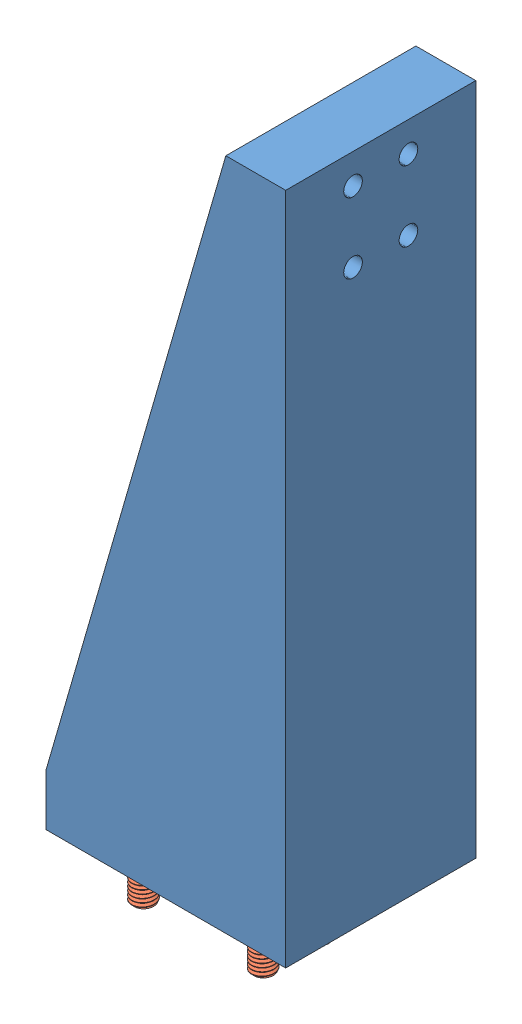
SolidWorks assembly Assem1, configuration Default. Lengths in mm.
Overall size (32 101.12 25.4).
5 component instances, 2 part files, 12 mates.
Components (placement in the parent):
- M40_Calibration Stand-1: M40_Calibration Stand [Default] at origin size (32 90 25.4)
- M43_91292A029_18-8 Stainless Steel Socket Head Screw-1: M43_91292A029_18-8 Stainless Steel Socket Head Screw [91292A029] at (20 -11 9) x (1 0 0) z (0 -1 0) size (5.5 5.5 21.26)
- M43_91292A029_18-8 Stainless Steel Socket Head Screw-2: M43_91292A029_18-8 Stainless Steel Socket Head Screw [91292A029] at (4 -11 9) x (1 0 0) z (0 -1 0) size (5.5 5.5 21.26)
- M43_91292A029_18-8 Stainless Steel Socket Head Screw-3: M43_91292A029_18-8 Stainless Steel Socket Head Screw [91292A029] at (4 -11 16.4) x (1 0 0) z (0 -1 0) size (5.5 5.5 21.26)
- M43_91292A029_18-8 Stainless Steel Socket Head Screw-4: M43_91292A029_18-8 Stainless Steel Socket Head Screw [91292A029] at (20 -11 16.4) x (1 0 0) z (0 -1 0) size (5.5 5.5 21.26)
Mates (geometry in assembly coordinates):
- Concentric1: concentric anti-aligned: cylinder of M40_Calibration Stand-1 through (20 -0.001 9) axis (0 1 0) radius 1.55; cylinder of M43_91292A029_18-8 Stainless Steel Socket Head Screw-1 through (20 10 9) axis (0 -1 0) radius 2.75
- Coincident1: coincident anti-aligned: plane of M40_Calibration Stand-1 through (0 7 25.4) normal (0 1 0); plane of M43_91292A029_18-8 Stainless Steel Socket Head Screw-1 through (20 7 9) normal (0 -1 0)
- Parallel1: parallel aligned: plane of M40_Calibration Stand-1 through (0 0 25.4) normal (-1 0 0); plane of M43_91292A029_18-8 Stainless Steel Socket Head Screw-1 through (21.25 8.125 9.7217) normal (-1 0 0)
- Concentric2: concentric anti-aligned: cylinder of M40_Calibration Stand-1 through (20 -0.001 16.4) axis (0 1 0) radius 1.55; cylinder of M43_91292A029_18-8 Stainless Steel Socket Head Screw-4 through (20 10 16.4) axis (0 -1 0) radius 2.75
- Coincident3: coincident anti-aligned: plane of M40_Calibration Stand-1 through (0 7 25.4) normal (0 1 0); plane of M43_91292A029_18-8 Stainless Steel Socket Head Screw-4 through (20 7 16.4) normal (0 -1 0)
- Parallel2: parallel aligned: plane of M40_Calibration Stand-1 through (0 0 25.4) normal (-1 0 0); plane of M43_91292A029_18-8 Stainless Steel Socket Head Screw-4 through (21.25 8.125 17.1217) normal (-1 0 0)
- Concentric3: concentric anti-aligned: cylinder of M40_Calibration Stand-1 through (4 -0.001 16.4) axis (0 1 0) radius 1.55; cylinder of M43_91292A029_18-8 Stainless Steel Socket Head Screw-3 through (4 10 16.4) axis (0 -1 0) radius 2.75
- Coincident6: coincident anti-aligned: plane of M40_Calibration Stand-1 through (0 7 25.4) normal (0 1 0); plane of M43_91292A029_18-8 Stainless Steel Socket Head Screw-3 through (4 7 16.4) normal (0 -1 0)
- Parallel4: parallel aligned: plane of M40_Calibration Stand-1 through (0 0 25.4) normal (-1 0 0); plane of M43_91292A029_18-8 Stainless Steel Socket Head Screw-3 through (5.25 8.125 17.1217) normal (-1 0 0)
- Concentric4: concentric: cylinder of M40_Calibration Stand-1 through (4 -0.001 9) axis (0 1 0) radius 1.55; cylinder of M43_91292A029_18-8 Stainless Steel Socket Head Screw-2 through (4 15.0109 9) axis (0 -1 0) radius 2.75
- Coincident9: coincident anti-aligned: plane of M40_Calibration Stand-1 through (0 7 25.4) normal (0 1 0); plane of M43_91292A029_18-8 Stainless Steel Socket Head Screw-2 through (4 7 9) normal (0 -1 0)
- Parallel5: parallel: plane of M40_Calibration Stand-1 through (0 0 25.4) normal (-1 0 0); plane of M43_91292A029_18-8 Stainless Steel Socket Head Screw-2 through (5.25 13.1359 9.7217) normal (-1 0 0)
